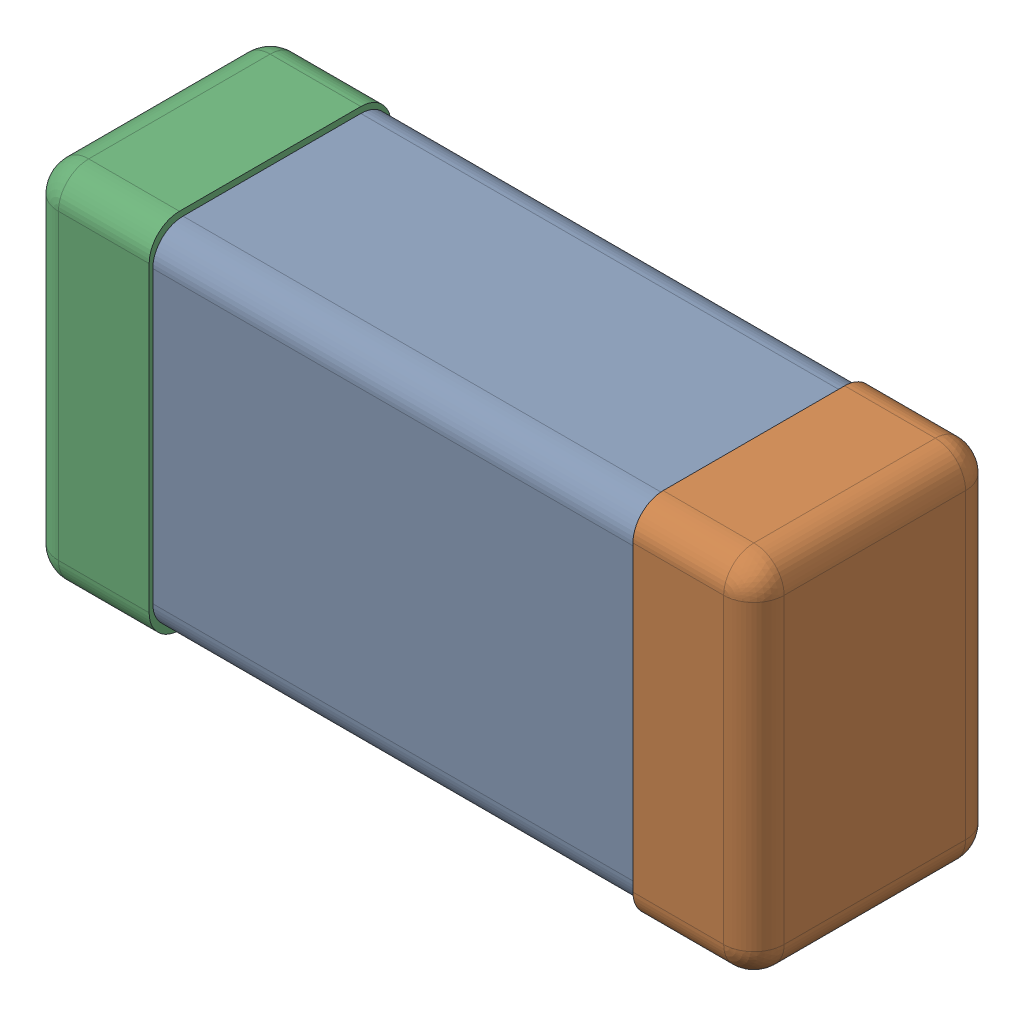
SolidWorks assembly C0201_020_24, configuration Standard. Lengths in mm.
Overall size (0.6 0.3 0.2).
4 component instances, 3 part files, 0 mates.
Components (placement in the parent):
- C0201_020_25-1: C0201_020_25 [Standard] at origin size (0.6 0.3 0.2)
  - Part 3_2-1: Part 3_2 [Standard] at (0 0 -7.3015) size (0.5 0.29 0.2)
  - Part 2_2-1: Part 2_2 [Standard] at (0 0 -7.3) size (0.1 0.3 0.2)
  - Part 1_2-1: Part 1_2 [Standard] at (0 0 -7.3) size (0.1 0.3 0.2)
